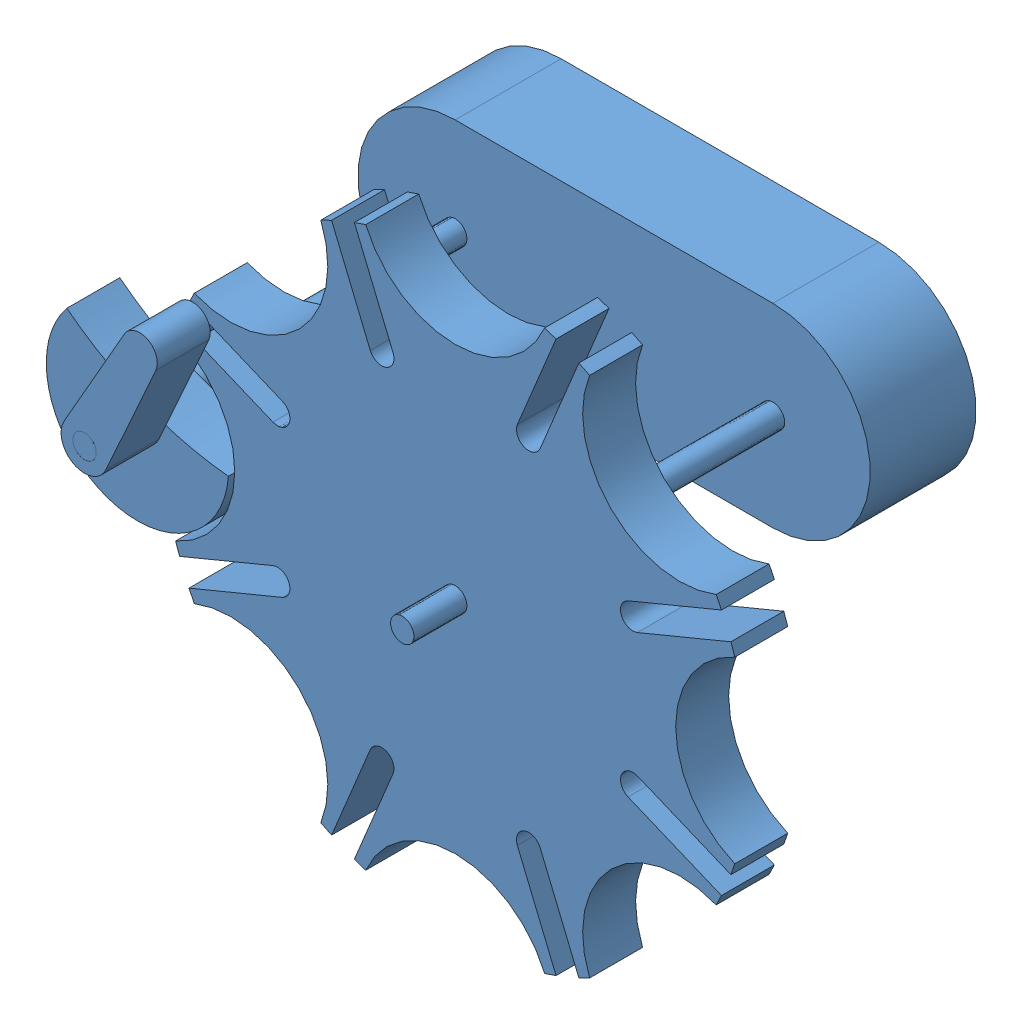
SolidWorks assembly Animacion_Ginebra, configuration Default. Lengths in mm.
Overall size (39.76 31.68 27).
3 component instances, 1 part files, 3 mates.
Components (placement in the parent):
- Rueda_Ginebra_7-1: Rueda_Ginebra_7 [Soporte] at (11.6462 31.5759 55.7866) size (29.02 11.02 27)
- Rueda_Ginebra_7-2: Rueda_Ginebra_7 [Disco_bloqueador] at (11.5913 30.1709 55.7866) x (0.996949 -0.078053 0) z (0 0 1) size (11.02 12.87 6)
- Rueda_Ginebra_7-3: Rueda_Ginebra_7 [Default] at (11.6462 31.5759 55.7866) size (31.68 31.68 3)
Mates (geometry in assembly coordinates):
- Coincidente1: coincident: circle of Rueda_Ginebra_7-1; circle of Rueda_Ginebra_7-2
- Concéntrica1: concentric: circle of Rueda_Ginebra_7-1; circle of Rueda_Ginebra_7-3
- Coincidente3: coincident: plane of Rueda_Ginebra_7-2 through (-2.9187 40.1509 55.7866) normal (0 0 1); plane of Rueda_Ginebra_7-3 through (11.6462 31.5759 55.7866) normal (0 0 1)
